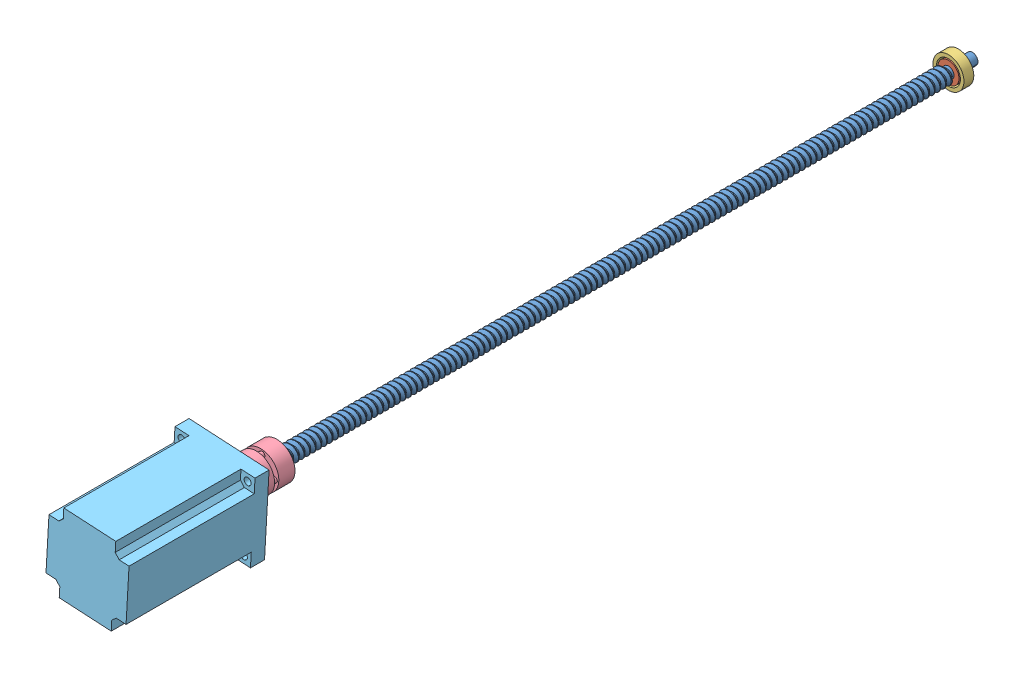
SolidWorks assembly X drive_1, configuration Default. Lengths in mm.
Overall size (60.15 60.15 629).
8 component instances, 6 part files, 6 mates.
Components (placement in the parent):
- X screw-1: X screw [Default] at (109.6527 -8.9932 132.9927) x (0 0 1) z (-0.999435 0.033604 0) size (506 14 12.14)
- 608 bearing-1: 608 bearing [Default] at (98.4609 -19.3648 -122.5346) x (-0.639932 -0.768431 0) z (0 0 1) size (22 22 7) (flexible)
  - inner race-1: inner race [Default] at (-10.3949 5.6455 9.7773) x (-0.344986 -0.938608 0) z (0 0 1) size (15 15 7)
  - outer race-1: outer race [Default] at (-10.3949 5.6455 9.7773) size (22 22 7)
- coupling WQ-C26L26-1: coupling WQ-C26L26 [Default] at (109.451 -14.9898 386.2427) x (0.108114 0.994139 0) z (0 0 1) size (26 26 26)
- 57 stepper motor-1: 57 stepper motor [Default] at (165.5663 -39.6064 373.5397) x (0.056863 0.998382 0) z (0 0 1) size (57 57 120) (flexible)
  - motor body-1: motor body [Default] at (21.3859 57.4242 33.703) size (57 57 100.6)
  - motor axis-1: motor axis [Default] at (21.3859 57.4242 33.703) x (-0.85154 0.52429 0) z (0 0 -1) size (8 8 21)
Mates (geometry in assembly coordinates):
- Concentric1: concentric anti-aligned: cylinder of X screw-1 through (109.451 -14.9898 383.2427) axis (0 0 1) radius 4; cylinder of 608 bearing-1/inner race-1 through (109.451 -14.9898 -105.7573) axis (0 0 -1) radius 4
- Distance1: distance = 10 mm aligned: plane of X screw-1 through (109.6527 -8.9932 -122.7573) normal (0 0 -1); plane of 608 bearing-1/inner race-1 through (109.451 -14.9898 -112.7573) normal (0 0 -1)
- Concentric5: concentric aligned: cylinder of X screw-1 through (109.451 -14.9898 383.2427) axis (0 0 1) radius 4; cylinder of coupling WQ-C26L26-1 through (109.451 -14.9898 371.7427) axis (0 0 1) radius 13
- Coincident15: coincident aligned: plane of X screw-1 through (109.6527 -8.9932 383.2427) normal (0 0 1); plane of coupling WQ-C26L26-1 through (109.451 -14.9898 383.2427) normal (0 0 1)
- Coincident21: coincident aligned: plane of coupling WQ-C26L26-1 through (109.451 -14.9898 386.2427) normal (0 0 -1); plane of 57 stepper motor-1/motor axis-1 through (109.451 -14.9898 386.2427) normal (0 0 -1)
- Concentric22: concentric anti-aligned: cylinder of coupling WQ-C26L26-1 through (109.451 -14.9898 397.7427) axis (0 0 -1) radius 4; cylinder of 57 stepper motor-1/motor axis-1 through (109.451 -14.9898 386.2427) axis (0 0 1) radius 4
